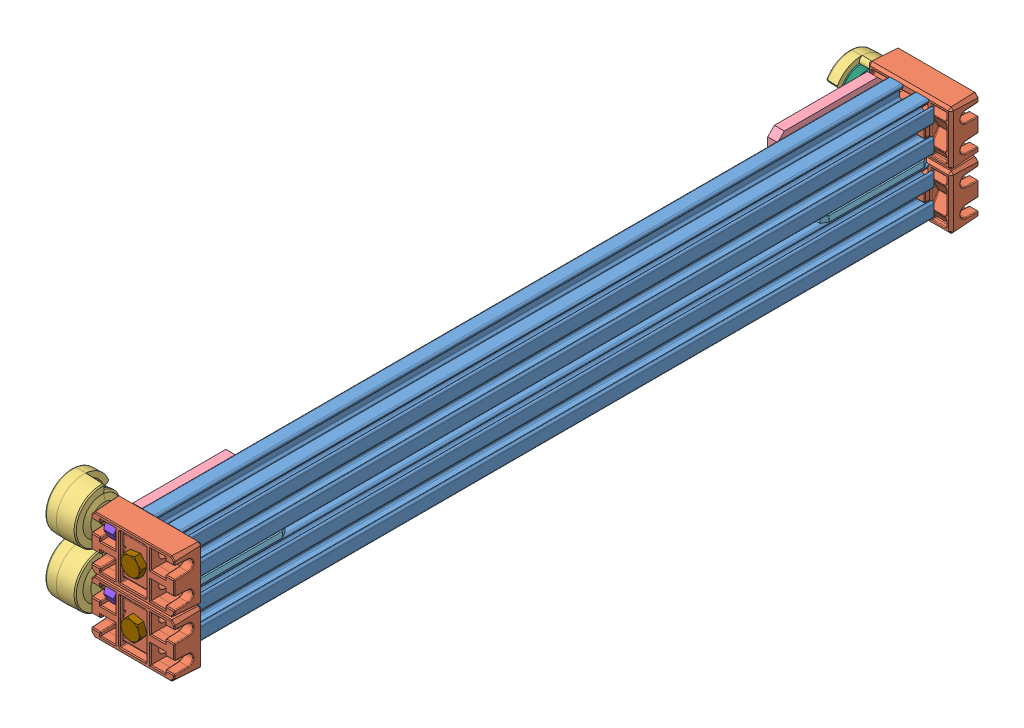
SolidWorks assembly REV-45-1507 (1), configuration Default. Lengths in mm.
Overall size (35.03 42.55 251.85).
49 component instances, 11 part files, 0 mates.
Components (placement in the parent):
- REV-45-1507 (1).STEP-1: REV-45-1507 (1).STEP [Default] at origin size (35.03 42.55 251.85)
  - single stage.STEP-1: single stage.STEP [Default] at origin size (35.03 35.21 251.41)
    - REV-41-1431.STEP-1: REV-41-1431.STEP [Default] at origin size (15 15 225)
    - REV-41-1511 V2.STEP-1: REV-41-1511 V2.STEP [Default] at (0 0 225) x (1 0 0) z (0 -1 0) size (25.27 10 16.27)
    - REV-41-1512 V2.STEP-1: REV-41-1512 V2.STEP [Default] at (-13.3855 4 229.5) x (0 -0.999636 0.026991) z (-1 0 0) size (16.25 15.38 9.77)
    - REV-41-1519.STEP-1: REV-41-1519.STEP [Default] at (-8.6 16.85 209) x (-1 0 0) z (0 0 1) size (7.02 29.79 32.41)
    - REV-41-1520.STEP-1: REV-41-1520.STEP [Default] at (0 8.35 209) x (0 -1 0) z (0 0 1) size (9.73 12.5 32.41)
    - REV-41-1511 V2.STEP-2: REV-41-1511 V2.STEP [Default] x (1 0 0) z (0 1 0) size (25.27 10 16.27)
    - REV-41-1512 V2.STEP-2: REV-41-1512 V2.STEP [Default] at (-13.3855 -4 -4.5) x (0 0.994583 -0.103946) z (-1 0 0) size (16.25 15.38 9.77)
    - REV-41-1368.STEP-1: REV-41-1368.STEP [Default] at (-17.6355 -4 -4.5) x (0 -0.999129 0.041719) z (0 0.041719 0.999129) size (12.02 4 12.02)
    - REV-41-1368.STEP-2: REV-41-1368.STEP [Default] at (-17.6355 4 229.5) x (0 -0.657313 0.753618) z (0 0.753618 0.657313) size (12.02 4 12.02)
  - single stage.STEP-2: single stage.STEP [Default] at (0 16.7 225) x (1 0 0) z (0 0 -1) size (35.03 35.21 251.41)
    - REV-41-1431.STEP-1: REV-41-1431.STEP [Default] at origin size (15 15 225)
    - REV-41-1511 V2.STEP-1: REV-41-1511 V2.STEP [Default] at (0 0 225) x (1 0 0) z (0 -1 0) size (25.27 10 16.27)
    - REV-41-1512 V2.STEP-1: REV-41-1512 V2.STEP [Default] at (-13.3855 4 229.5) x (0 -0.999636 0.026991) z (-1 0 0) size (16.25 15.38 9.77)
    - REV-41-1519.STEP-1: REV-41-1519.STEP [Default] at (-8.6 16.85 209) x (-1 0 0) z (0 0 1) size (7.02 29.79 32.41)
    - REV-41-1520.STEP-1: REV-41-1520.STEP [Default] at (0 8.35 209) x (0 -1 0) z (0 0 1) size (9.73 12.5 32.41)
    - REV-41-1511 V2.STEP-2: REV-41-1511 V2.STEP [Default] x (1 0 0) z (0 1 0) size (25.27 10 16.27)
    - REV-41-1512 V2.STEP-2: REV-41-1512 V2.STEP [Default] at (-13.3855 -4 -4.5) x (0 0.994583 -0.103946) z (-1 0 0) size (16.25 15.38 9.77)
    - REV-41-1368.STEP-1: REV-41-1368.STEP [Default] at (-17.6355 -4 -4.5) x (0 -0.999129 0.041719) z (0 0.041719 0.999129) size (12.02 4 12.02)
    - REV-41-1368.STEP-2: REV-41-1368.STEP [Default] at (-17.6355 4 229.5) x (0 -0.657313 0.753618) z (0 0.753618 0.657313) size (12.02 4 12.02)
  - REV-41-1359 Simple.STEP-1: REV-41-1359 Simple.STEP [Default] at (-4.3 16.7 8) x (0 -0.430498 -0.902592) z (0 0.902592 -0.430498) size (6.36 10.01 6.36)
  - REV-41-1361 Simple.STEP-1: REV-41-1361 Simple.STEP [Default] at (-10.5 16.7 8) x (0 -0.445235 -0.895414) z (0 0.895414 -0.445235) size (5.94 4.01 6.36)
  - REV-41-1359 Simple.STEP-2: REV-41-1359 Simple.STEP [Default] at (-4.3 16.7 24) x (0 -0.580691 -0.814124) z (0 0.814124 -0.580691) size (6.36 10.01 6.36)
  - REV-41-1361 Simple.STEP-2: REV-41-1361 Simple.STEP [Default] at (-10.5 16.7 24) x (0 -0.593958 -0.804496) z (0 0.804496 -0.593958) size (5.94 4.01 6.36)
  - REV-41-1359 Simple.STEP-3: REV-41-1359 Simple.STEP [Default] at (-4.3 0 201) x (0 -0.71324 -0.70092) z (0 0.70092 -0.71324) size (6.36 10.01 6.36)
  - REV-41-1361 Simple.STEP-3: REV-41-1361 Simple.STEP [Default] at (-10.5 0 201) x (0 -0.724633 -0.689135) z (0 0.689135 -0.724633) size (5.94 4.01 6.36)
  - REV-41-1359 Simple.STEP-4: REV-41-1359 Simple.STEP [Default] at (-4.3 0 217) x (0 -0.824118 -0.566419) z (0 0.566419 -0.824118) size (6.36 10.01 6.36)
  - REV-41-1361 Simple.STEP-4: REV-41-1361 Simple.STEP [Default] at (-10.5 0 217) x (0 -0.833292 -0.552834) z (0 0.552834 -0.833292) size (5.94 4.01 6.36)
  - REV-41-1360 Simple.STEP-1: REV-41-1360 Simple.STEP [Default] at (-21.6355 20.7 229.5) x (0 0.109387 0.993999) z (0 0.993999 -0.109387) size (6.36 18.01 6.36)
  - REV-41-1360 Simple.STEP-2: REV-41-1360 Simple.STEP [Default] at (-21.6355 4 229.5) x (0 -0.222279 0.974983) z (0 0.974983 0.222279) size (6.36 18.01 6.36)
  - REV-41-1360 Simple.STEP-3: REV-41-1360 Simple.STEP [Default] at (-21.6355 12.7 -4.5) x (0 -0.344617 0.938743) z (0 0.938743 0.344617) size (6.36 18.01 6.36)
  - REV-41-1360 Simple.STEP-4: REV-41-1360 Simple.STEP [Default] at (0 16.7 -9.3) x (0.896929 0.442175 0) z (0.442175 -0.896929 0) size (6.36 18.01 6.36)
  - REV-41-1360 Simple.STEP-5: REV-41-1360 Simple.STEP [Default] at (0 0 -9.3) x (0.896929 0.442175 0) z (0.442175 -0.896929 0) size (6.36 18.01 6.36)
  - REV-41-1360 Simple.STEP-6: REV-41-1360 Simple.STEP [Default] at (0 16.7 234.3) x (-0.153031 0.988221 0) z (-0.988221 -0.153031 0) size (6.36 18.01 6.36)
  - REV-41-1360 Simple.STEP-7: REV-41-1360 Simple.STEP [Default] at (0 0 234.3) x (-0.194189 -0.980964 0) z (0.980964 -0.194189 0) size (6.36 18.01 6.36)
  - REV-41-1360 Simple.STEP-8: REV-41-1360 Simple.STEP [Default] at (-21.6355 -4 -4.5) x (0 -0.489098 0.872229) z (0 0.872229 0.489098) size (6.36 18.01 6.36)
  - REV-41-1361 Simple.STEP-5: REV-41-1361 Simple.STEP [Default] at (-9.8355 -4 -4.5) x (0 0.529919 0.848048) z (0 0.848048 -0.529919) size (5.94 4.01 6.36)
  - REV-41-1361 Simple.STEP-6: REV-41-1361 Simple.STEP [Default] at (-9.8355 12.7 -4.5) x (0 0.529919 0.848048) z (0 0.848048 -0.529919) size (5.94 4.01 6.36)
  - REV-41-1361 Simple.STEP-7: REV-41-1361 Simple.STEP [Default] at (-9.8355 4 229.5) x (0 -0.5 -0.866025) z (0 -0.866025 0.5) size (5.94 4.01 6.36)
  - REV-41-1361 Simple.STEP-8: REV-41-1361 Simple.STEP [Default] at (-9.8355 20.7 229.5) x (0 -0.5 -0.866025) z (0 -0.866025 0.5) size (5.94 4.01 6.36)
  - M3 x 8mm low profile socket.STEP-1: M3 x 8mm low profile socket.STEP [Default] at (0 5.65 24) x (-0.837169 0 -0.546944) z (-0.546944 0 0.837169) size (5.4 9.8 5.4)
  - hex nut style 1_am_B18.2.4.1M - Hex nut, Style 1,  M3 x 0.5 --D-N.STEP-1: hex nut style 1_am_B18.2.4.1M - Hex nut, Style 1,  M3 x 0.5 --D-N.STEP [Default] at (0 13.2 24) x (0.5 0 -0.866025) z (0 1 0) size (6.36 6.36 2.41)
  - M3 x 8mm low profile socket.STEP-2: M3 x 8mm low profile socket.STEP [Default] at (0 5.65 8) x (-0.925243 0 -0.379375) z (-0.379375 0 0.925243) size (5.4 9.8 5.4)
  - hex nut style 1_am_B18.2.4.1M - Hex nut, Style 1,  M3 x 0.5 --D-N.STEP-2: hex nut style 1_am_B18.2.4.1M - Hex nut, Style 1,  M3 x 0.5 --D-N.STEP [Default] at (0 13.2 8) x (1 0 0) z (0 1 0) size (6.36 6.36 2.41)
  - hex nut style 1_am_B18.2.4.1M - Hex nut, Style 1,  M3 x 0.5 --D-N.STEP-3: hex nut style 1_am_B18.2.4.1M - Hex nut, Style 1,  M3 x 0.5 --D-N.STEP [Default] at (0 3.5 217) x (-0.5 0 0.866025) z (0 -1 0) size (6.36 6.36 2.41)
  - M3 x 8mm low profile socket.STEP-3: M3 x 8mm low profile socket.STEP [Default] at (0 11.05 217) x (-0.546944 0 -0.837169) z (0.837169 0 -0.546944) size (5.4 9.8 5.4)
  - hex nut style 1_am_B18.2.4.1M - Hex nut, Style 1,  M3 x 0.5 --D-N.STEP-4: hex nut style 1_am_B18.2.4.1M - Hex nut, Style 1,  M3 x 0.5 --D-N.STEP [Default] at (0 3.5 201) x (-0.5 0 0.866025) z (0 -1 0) size (6.36 6.36 2.41)
  - M3 x 8mm low profile socket.STEP-4: M3 x 8mm low profile socket.STEP [Default] at (0 11.05 201) x (-0.546944 0 -0.837169) z (0.837169 0 -0.546944) size (5.4 9.8 5.4)
